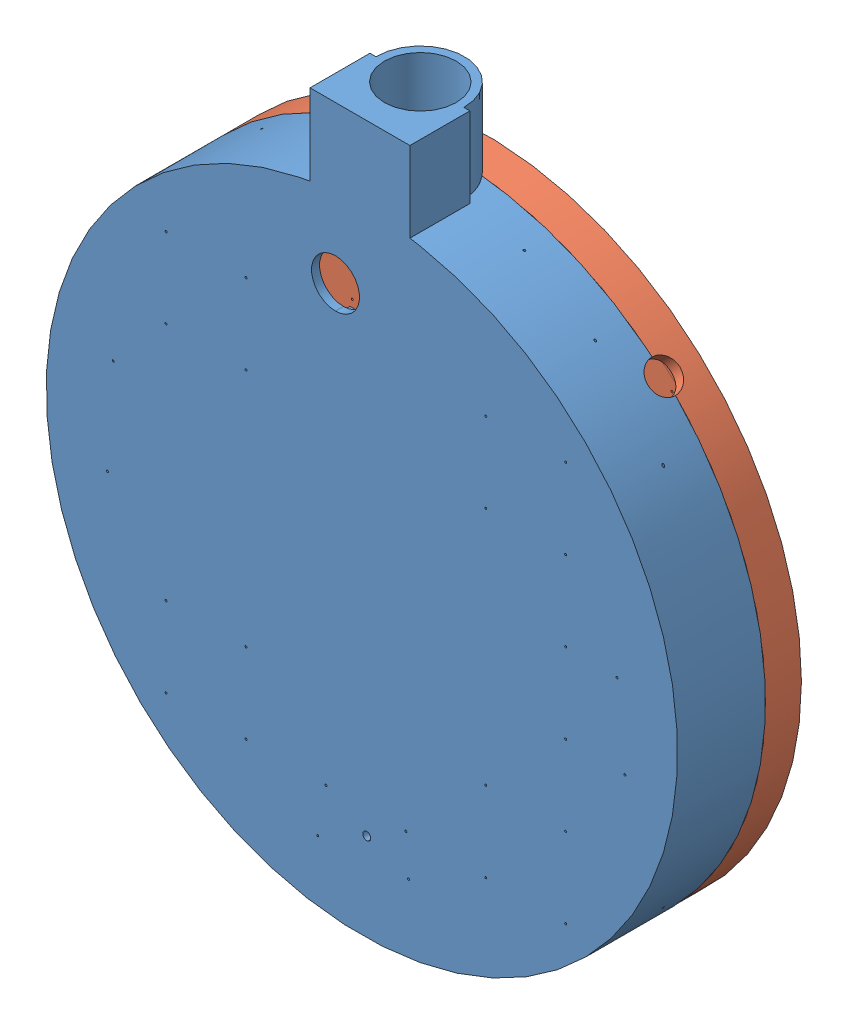
SolidWorks assembly Sestava_forma_Semafor_2, configuration Výchozí. Lengths in mm.
Overall size (158 177.16 31).
2 component instances, 2 part files, 3 mates.
Components (placement in the parent):
- Pulka_top_Semafor2-1: Pulka_top_Semafor2 [Výchozí] at origin size (158 177.16 26.1)
- Pulka_bottom_Semafor2-1: Pulka_bottom_Semafor2 [Výchozí] at origin size (158 158 23)
Mates (geometry in assembly coordinates):
- Soustředná1: concentric aligned: circle of Pulka_top_Semafor2-1; circle of Pulka_bottom_Semafor2-1
- Sjednocená2: coincident anti-aligned: plane of Pulka_top_Semafor2-1 through (-100 99.9315 -1.4) normal (-0.766044 0.642788 0); plane of Pulka_bottom_Semafor2-1 through (-157.8509 30.9875 -13.4) normal (0.766044 -0.642788 0)
- Sjednocená3: coincident anti-aligned: plane of Pulka_top_Semafor2-1 through (-100 99.9315 -1.4) normal (0 0 -1); plane of Pulka_bottom_Semafor2-1 through (-100 99.9315 -1.4) normal (0 0 1)
